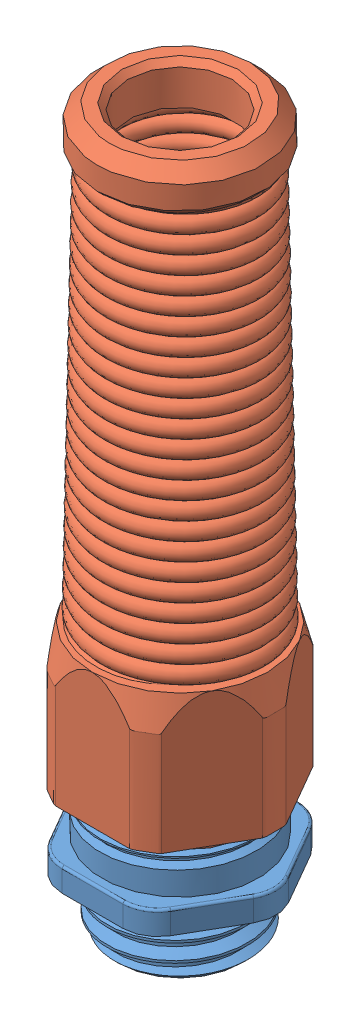
SolidWorks assembly Сборка3, configuration По умолчанию. Lengths in mm.
Overall size (16.98 61.73 15.24).
2 component instances, 2 part files, 0 mates.
Components (placement in the parent):
- основание-1: основание [По умолчанию] at origin size (16.39 17.89 15)
- гайка-1: гайка [По умолчанию] at (0 4.7 0) size (16.98 50.86 15.24)
